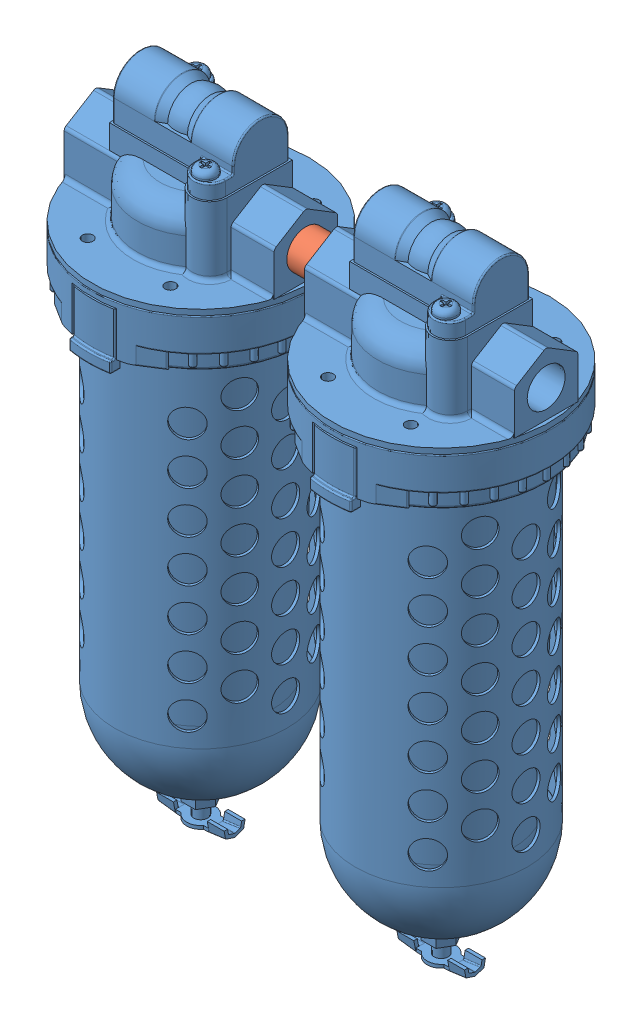
SolidWorks assembly ReadingTech_3P-060-P03-DCPi, configuration Default. Lengths in mm.
Overall size (206.63 287.65 99.95).
3 component instances, 2 part files, 3 mates.
Components (placement in the parent):
- ReadingTech_3P-060-P03-Pi-1: ReadingTech_3P-060-P03-Pi [Default] at (-22.8132 -101.3128 3.3181) size (98.17 287.65 99.95)
- ReadingTech_3P-060-P03-Pi-2: ReadingTech_3P-060-P03-Pi [Default] at (85.6448 -101.3128 3.3181) size (98.17 287.65 99.95)
- ReadingTech- 60cfm_connector_.375in-1: ReadingTech- 60cfm_connector_.375in [Default] at (38.2738 114.5872 3.3181) x (0 1 0) z (0 0 1) size (17.14 13.72 17.14)
Mates (geometry in assembly coordinates):
- Coincident1: coincident anti-aligned: circle of ReadingTech_3P-060-P03-Pi-1; circle of ReadingTech- 60cfm_connector_.375in-1
- Coincident2: coincident aligned: circle of ReadingTech_3P-060-P03-Pi-2; circle of ReadingTech- 60cfm_connector_.375in-1
- Coincident3: coincident aligned: plane of ReadingTech_3P-060-P03-Pi-1 through (24.5578 101.8872 17.6056) normal (0 0 1); plane of ReadingTech_3P-060-P03-Pi-2 through (133.0158 101.8872 17.6056) normal (0 0 1)
